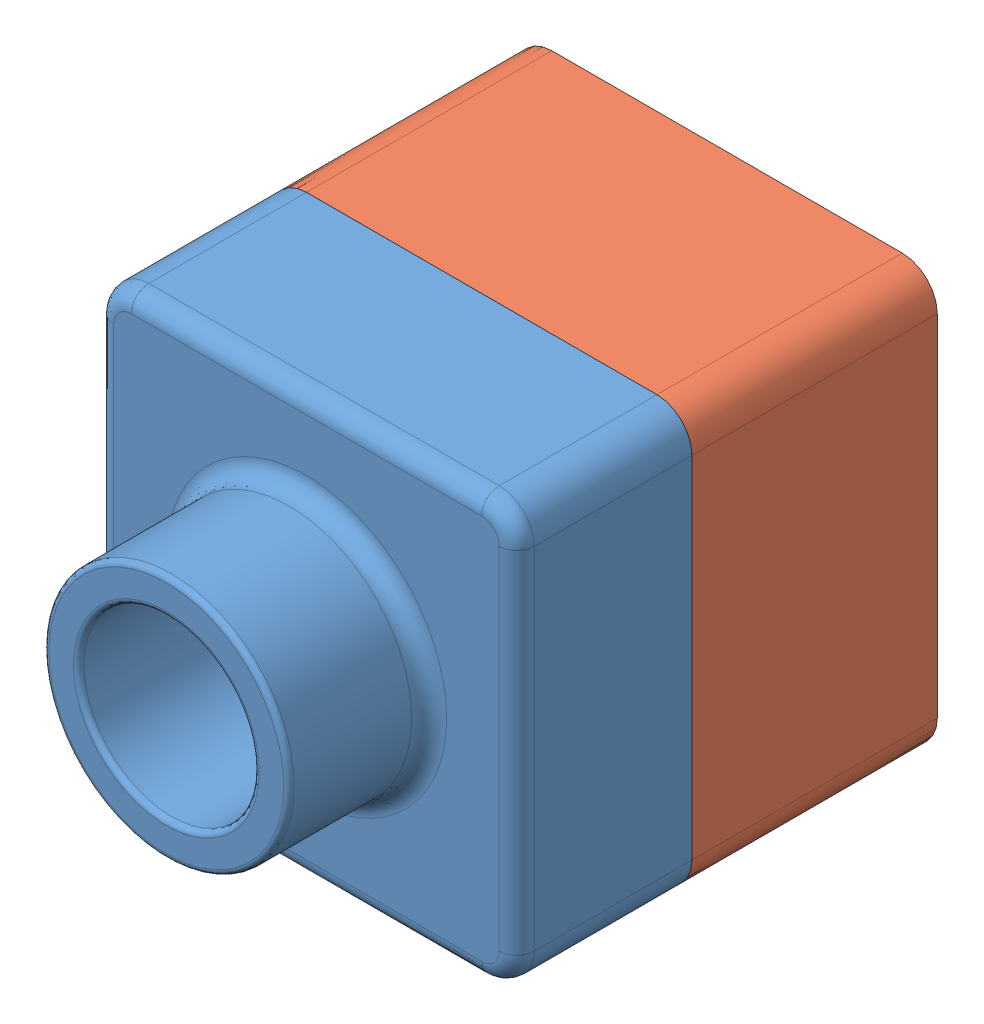
SolidWorks assembly Tutor, configuration Default. Lengths in mm.
Overall size (120 120 160).
2 component instances, 2 part files, 3 mates.
Components (placement in the parent):
- Tutor1-1: Tutor1 [Default] at (-26.2589 60.9199 130.76) size (120 120 90)
- Tutor2-1: Tutor2 [Default] at (-26.2589 60.9199 60.76) size (120 120 90)
Mates (geometry in assembly coordinates):
- Coincident2: coincident anti-aligned: line of Tutor1-1 through (-26.2589 180.9199 130.76) axis (1 0 0); line of Tutor2-1 through (83.7411 180.9199 130.76) axis (-1 0 0)
- Coincident3: coincident aligned: plane of Tutor1-1 through (93.7411 60.9199 180.76) normal (1 0 0); plane of Tutor2-1 through (93.7411 60.9199 150.76) normal (1 0 0)
- Coincident5: coincident aligned: plane of Tutor1-1 through (-26.2589 180.9199 180.76) normal (0 1 0); plane of Tutor2-1 through (-26.2589 180.9199 150.76) normal (0 1 0)
